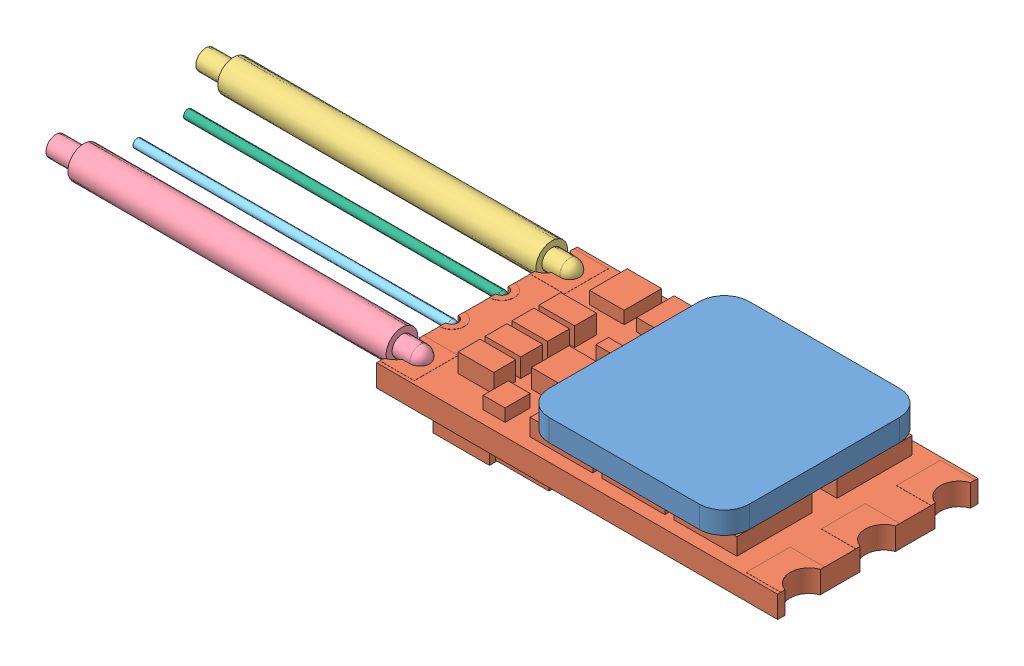
SolidWorks assembly Aria 35A, configuration Default. Lengths in mm.
Overall size (59.62 7.2 16).
8 component instances, 7 part files, 0 mates.
Components (placement in the parent):
- Aria 35A.stp-1: Aria 35A.stp [Default] at origin size (59.62 8.35 17)
  - Heatsink.stp-1: Heatsink.stp [Default] at (-12.7702 2.9216 0) size (16 1.75 16)
  - Circuit Board.stp-1: Circuit Board.stp [Default] at (-16.5202 0.6966 0) size (32 5.6 16)
  - Cable (Red).stp-1: Cable (Red).stp [Default] at (-57.9202 1.7403 -5.98) x (1 0 0) z (0 0.737302 -0.675563) size (29.84 2.54 2.54)
  - Cable (Red)_1.stp-1: Cable (Red)_1.stp [Default] at (-57.9202 1.7403 5.98) x (1 0 0) z (0 -0.745208 -0.666833) size (29.84 2.54 2.54)
  - PWM (Black).stp-1: PWM (Black).stp [Default] at (-57.6027 1.2223 2.0137) x (1 0 0) z (0 0.011248 0.999937) size (25.4 0.7 0.7)
  - PWM (Black)_1.stp-1: PWM (Black)_1.stp [Default] at (-57.6027 1.2223 -2.0137) x (1 0 0) z (0 -0.020245 0.999795) size (25.4 0.7 0.7)
  - HeatShrink.stp-1: HeatShrink.stp [Default] at (-32.5202 0.9966 0) x (1 0 0) z (0 0 -1) size (28 8.35 17) (hidden)
